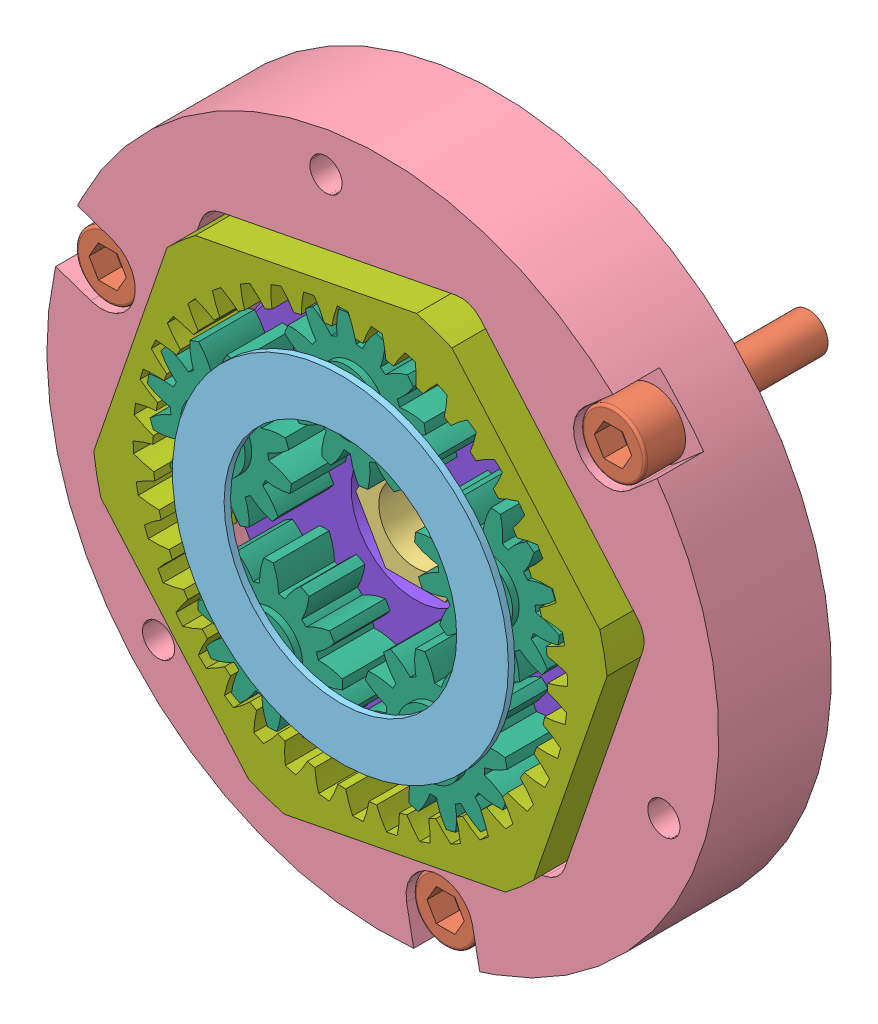
SolidWorks assembly GEM+Single+Stage, configuration Default. Lengths in mm.
Overall size (96.8 96.8 30).
18 component instances, 8 part files, 0 mates.
Components (placement in the parent):
- GEM Dowel-1: GEM Dowel [Default] at (-16.4188 5.3615 0) x (-0.809017 0.587785 0) z (0 0 1) size (4.76 4.76 11.11)
- SHCS 10-32 x 0.75-1: SHCS 10-32 x 0.75 [Default] at (6.9779 -35.8395 2.6035) size (7.85 7.85 24.03)
- GEM SUN Gear 15t-1: GEM SUN Gear 15t [Default] x (0.5 0.866025 0) z (0 0 -1) size (21.56 21.46 13.06)
- GEM Dowel-2: GEM Dowel [Default] at (16.4345 5.3132 0) x (0.309017 -0.951057 0) z (0 0 1) size (4.76 4.76 11.11)
- GEM Stage Housing-1: GEM Stage Housing [Default] at (0 0 -5.5245) x (0.981569 0.191109 0) z (0 0 1) size (82.55 82.55 13.84)
- SHCS 10-32 x 0.75-2: SHCS 10-32 x 0.75 [Default] at (27.549 23.9628 2.6035) x (-0.5 0.866025 0) z (0 0 1) size (7.85 7.85 24.03)
- GEM Ring Bushing-1: GEM Ring Bushing [Default] at (7.9656 -20.0165 13.5509) size (41.27 41.27 0.79)
- GEM Spur Gear 12t-1: GEM Spur Gear 12t [Default] at (-16.4188 5.3615 11.9697) x (-0.348663 0.937248 0) z (0 0 -1) size (17.78 17.78 8.45)
- GEM Spur Gear 12t-2: GEM Spur Gear 12t [Default] at (10.1317 -13.9883 11.9697) x (-0.304784 -0.952422 0) z (0 0 -1) size (17.78 17.78 8.45)
- GEM Dowel-3: GEM Dowel [Default] at (0.0254 17.272 0) x (0.309017 0.951057 0) z (0 0 1) size (4.76 4.76 11.11)
- GEM Spur Gear 12t-3: GEM Spur Gear 12t [Default] at (16.4345 5.3132 11.9697) x (0.601687 0.798732 0) z (0 0 -1) size (17.78 17.78 8.45)
- GEM Dowel-4: GEM Dowel [Default] at (-10.1728 -13.9584 0) x (-0.809017 -0.587785 0) z (0 0 1) size (4.76 4.76 11.11)
- GEM Ring Gear-1: GEM Ring Gear [Default] at (-0.0477 -0.1387 4.318) x (0.191109 -0.981569 0) z (0 0 -1) size (57.15 63.5 7.94)
- GEM Spur Gear 12t-4: GEM Spur Gear 12t [Default] at (-10.1728 -13.9584 11.9697) x (-0.99971 -0.024068 0) z (0 0 -1) size (17.78 17.78 8.45)
- GEM Carrier Plate-1: GEM Carrier Plate [Default] at origin size (47.57 47.57 4.47)
- GEM Dowel-5: GEM Dowel [Default] at (10.1317 -13.9883 0) size (4.76 4.76 11.11)
- SHCS 10-32 x 0.75-3: SHCS 10-32 x 0.75 [Default] at (-34.5269 11.8768 2.6035) x (-0.5 -0.866025 0) z (0 0 1) size (7.85 7.85 24.03)
- GEM Spur Gear 12t-5: GEM Spur Gear 12t [Default] at (0.0254 17.272 11.9697) x (0.926545 -0.376185 0) z (0 0 -1) size (17.78 17.78 8.45)
